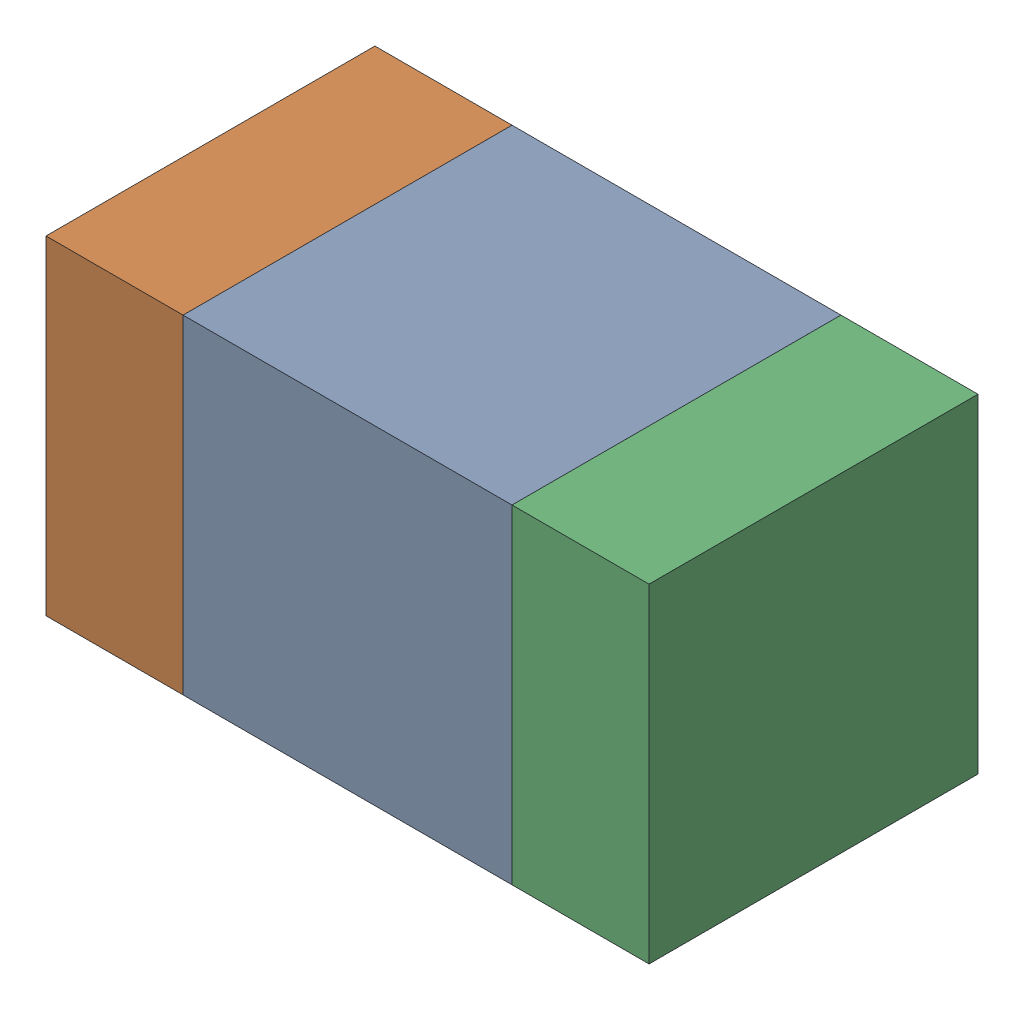
SolidWorks assembly C300_2PCB, configuration Default. Lengths in mm.
Overall size (1.1 0.6 0.6).
6 component instances, 2 part files, 0 mates.
Components (placement in the parent):
- 761606048-1: 761606048 [Default] at (145.6752 98.6181 0) size (0.6 0.6 0.6)
  - Extruded_9-1: Extruded_9 [Default] at origin size (0.6 0.6 0.6)
- 854785160-1: 854785160 [Default] at (145.2502 98.6181 0) size (0.25 0.6 0.6)
  - Extruded_19-1: Extruded_19 [Default] at origin size (0.25 0.6 0.6)
- 854785160-2: 854785160 [Default] at (146.1003 98.6181 0) size (0.25 0.6 0.6)
  - Extruded_19-1: Extruded_19 [Default] at origin size (0.25 0.6 0.6)
